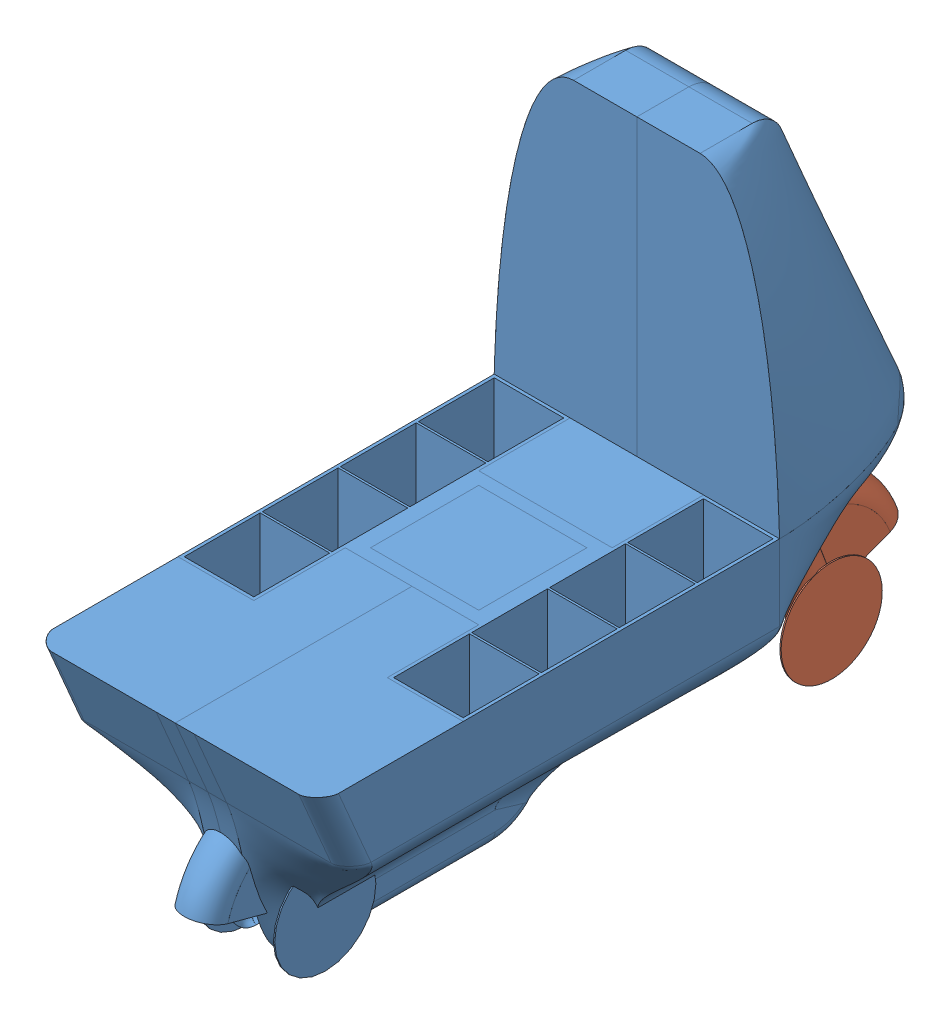
SolidWorks assembly assemb body, configuration Default. Lengths in mm.
Overall size (459.1 2067.81 2573.45).
2 component instances, 2 part files, 2 mates.
Components (placement in the parent):
- main body-1: main body [Default] at (626.9492 1061.4122 1381.2257) size (459.1 1844.57 1364.93)
- frontwheel body-1: frontwheel body [Default] at (626.73 1251.6951 883.1306) x (0.000768 -0.666738 0.745292) z (-1 -0.000293 0.000768) size (1277.02 1589.76 136.93)
Mates (geometry in assembly coordinates):
- Concentric2: concentric anti-aligned: circle of main body-1; circle of frontwheel body-1
- Coincident3: coincident anti-aligned: circle of main body-1; circle of frontwheel body-1
